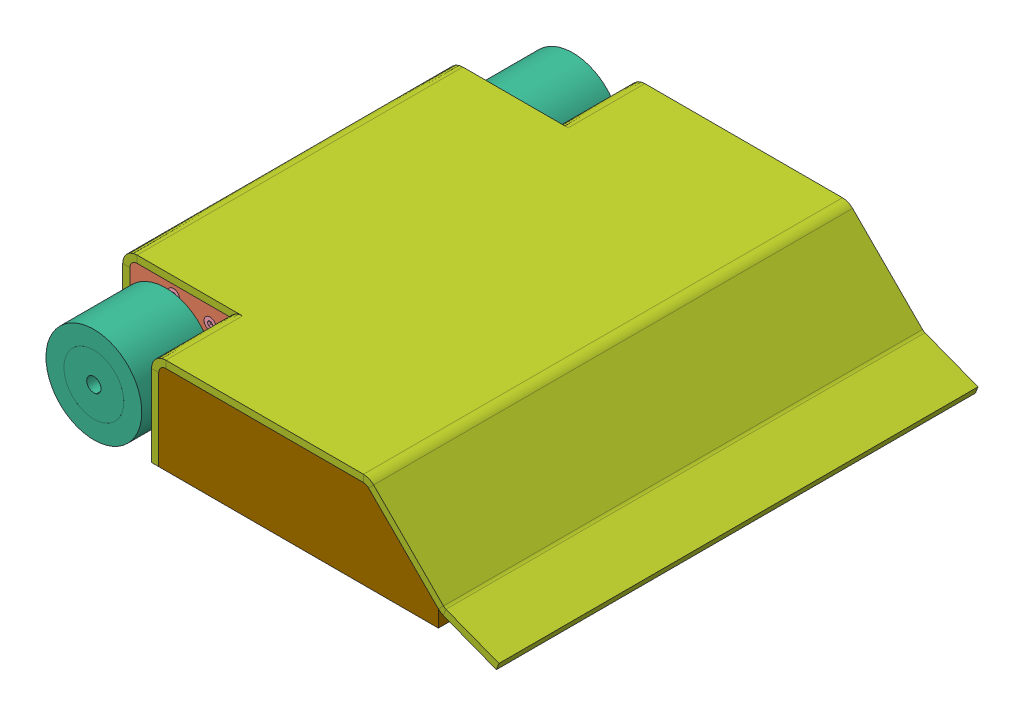
SolidWorks assembly Robot, configuration Predeterminado. Lengths in mm.
Overall size (194.79 51.27 200).
30 component instances, 9 part files, 12 mates.
Components (placement in the parent):
- Traccion-1: Traccion [Predeterminado] at (25.1389 -0.4044 74) size (55.68 51.27 200)
  - Struct_1-1: Struct_1 [Predeterminado] at (-7.0782 16.7308 63) size (5 37 126)
  - Bracket_motorD-1: Bracket_motorD [Predeterminado] at (-28.0782 3.2308 189) size (47 37 5)
  - Bracket_motorI-1: Bracket_motorI [Predeterminado] at (-28.0782 3.2308 58) size (47 37 5)
  - Tornillo M3x15-1: Tornillo M3x15 [Predeterminado] at (-7.0828 -10.2692 179) size (5 5 15.24)
  - Tornillo M3x15-2: Tornillo M3x15 [Predeterminado] at (-7.0828 16.7308 179) size (5 5 15.24)
  - Tornillo M3x15-3: Tornillo M3x15 [Predeterminado] at (-7.0828 -10.2692 73) x (1 0 0) z (0 0 -1) size (5 5 15.24)
  - Tornillo M3x15-4: Tornillo M3x15 [Predeterminado] at (-7.0828 16.7308 73) x (1 0 0) z (0 0 -1) size (5 5 15.24)
  - Tornillo M3x15-5: Tornillo M3x15 [Predeterminado] at (-18.1216 15.0668 179) size (5 5 15.24)
  - Tornillo M3x15-6: Tornillo M3x15 [Predeterminado] at (-38.0347 -8.6051 179) size (5 5 15.24)
  - Tornillo M3x15-7: Tornillo M3x15 [Predeterminado] at (-33.3501 17.7714 179) size (5 5 15.24)
  - Tornillo M3x15-8: Tornillo M3x15 [Predeterminado] at (-22.8062 -11.3098 179) size (5 5 15.24)
  - Tornillo M3x15-9: Tornillo M3x15 [Predeterminado] at (-43.3067 5.9355 179) size (5 5 15.24)
  - Tornillo M3x15-10: Tornillo M3x15 [Predeterminado] at (-12.8497 0.5262 179) size (5 5 15.24)
  - Tornillo M3x15-11: Tornillo M3x15 [Predeterminado] at (-22.8062 -11.3098 73) x (-1 0 0) z (0 0 -1) size (5 5 15.24)
  - Tornillo M3x15-12: Tornillo M3x15 [Predeterminado] at (-18.1216 15.0668 73) x (-1 0 0) z (0 0 -1) size (5 5 15.24)
  - Tornillo M3x15-13: Tornillo M3x15 [Predeterminado] at (-12.8497 0.5262 73) x (-1 0 0) z (0 0 -1) size (5 5 15.24)
  - Tornillo M3x15-14: Tornillo M3x15 [Predeterminado] at (-33.3501 17.7714 73) x (-1 0 0) z (0 0 -1) size (5 5 15.24)
  - Tornillo M3x15-15: Tornillo M3x15 [Predeterminado] at (-43.3067 5.9355 73) x (-1 0 0) z (0 0 -1) size (5 5 15.24)
  - Tornillo M3x15-16: Tornillo M3x15 [Predeterminado] at (-38.0347 -8.6051 73) x (-1 0 0) z (0 0 -1) size (5 5 15.24)
  - Motor+Rueda-1: Motor+Rueda [Predeterminado] at (-36.1449 1.5801 91.875) x (-0.939693 -0.34202 0) z (0 0 1) size (40 40 170.38)
    - Titan-37mm-500rpm-2: Titan-37mm-500rpm [Predeterminado] at (-8.182 1.2078 75.625) x (0 1 0) z (0 0 1) size (37 37 78.75)
    - js4030-wheel-cad-1: js4030-wheel-cad [Predeterminado] at (-21.4262 1.7536 159.125) x (-1 0 0) z (0 0 -1) size (40 40 30)
  - Motor+Rueda-2: Motor+Rueda [Predeterminado] at (-35.3187 -0.6899 160.125) x (-0.939693 -0.34202 0) z (0 0 -1) size (40 40 170.38)
    - Titan-37mm-500rpm-2: Titan-37mm-500rpm [Predeterminado] at (-8.182 1.2078 75.625) x (0 1 0) z (0 0 1) size (37 37 78.75)
    - js4030-wheel-cad-1: js4030-wheel-cad [Predeterminado] at (-21.4262 1.7536 159.125) x (-1 0 0) z (0 0 -1) size (40 40 30)
- Chapa-1: Chapa [Predeterminado] at (-1.4393 21.3264 200) size (189.11 42.9 200)
- Bateria-1: Bateria [Predeterminado] at (51.0607 -13.6736 200) x (0 0 -1) z (1 0 0) size (136 27 45)
- Laterales-1: Laterales [Predeterminado] at (17.5607 -15.6736 100) size (116.8 37 5)
- Laterales-2: Laterales [Predeterminado] at (17.5607 -15.6736 295) size (116.8 37 5)
Mates (geometry in assembly coordinates):
- Coincidente1: coincident aligned: plane of Traccion-1/Bracket_motorD-1 through (-2.9393 2.8264 268) normal (0 0 1); plane of Chapa-1 through (-23.4393 24.3264 268) normal (0 0 1)
- Coincidente2: coincident anti-aligned: plane of Traccion-1/Bracket_motorD-1 through (-21.4393 21.3264 268) normal (0 1 0); plane of Chapa-1 through (-1.4393 21.3264 200) normal (0 -1 0)
- Coincidente4: coincident: line of Traccion-1/Bracket_motorD-1 through (-26.4393 -2.4309 268) axis (0 1 0); line of Chapa-1 through (-26.4393 -2.4309 268) axis (0 1 0)
- Ancho1: width: plane of Bateria-1 through (73.5607 13.3264 268) normal (0 0 1); plane of Bateria-1 through (73.5607 13.3264 132) normal (0 0 -1); plane of Traccion-1/Bracket_motorI-1 through (-2.9393 2.8264 132) normal (0 0 -1); plane of Traccion-1/Bracket_motorD-1 through (-2.9393 2.8264 268) normal (0 0 1)
- Distancia1: distance = 8 mm anti-aligned: plane of Bateria-1 through (51.0607 13.3264 200) normal (0 1 0); plane of Chapa-1 through (-1.4393 21.3264 200) normal (0 -1 0)
- Distancia2: distance = 8 mm anti-aligned: plane of Bateria-1 through (28.5607 13.3264 268) normal (-1 0 0); plane of Traccion-1/Struct_1-1 through (20.5607 11.3264 263) normal (1 0 0)
- Coincidente7: coincident aligned: plane of Chapa-1 through (137.3805 -7.4934 300) normal (0 0 1); plane of Laterales-2 through (103.0754 18.3264 300) normal (0 0 1)
- Coincidente8: coincident aligned: circle of Chapa-1; circle of Laterales-2
- Coincidente9: coincident aligned: plane of Chapa-1 through (105.5607 24.3264 100) normal (0 0 -1); plane of Laterales-1 through (103.0754 18.3264 100) normal (0 0 -1)
- Coincidente10: coincident anti-aligned: circle of Chapa-1; circle of Laterales-1
- Coincidente11: coincident aligned: line of Chapa-1 through (103.0754 21.3264 100) axis (-1 0 0); line of Laterales-1 through (103.0754 21.3264 100) axis (-1 0 0)
- Coincidente12: coincident anti-aligned: line of Chapa-1 through (20.5607 21.3264 300) axis (1 0 0); line of Laterales-2 through (103.0754 21.3264 300) axis (-1 0 0)
